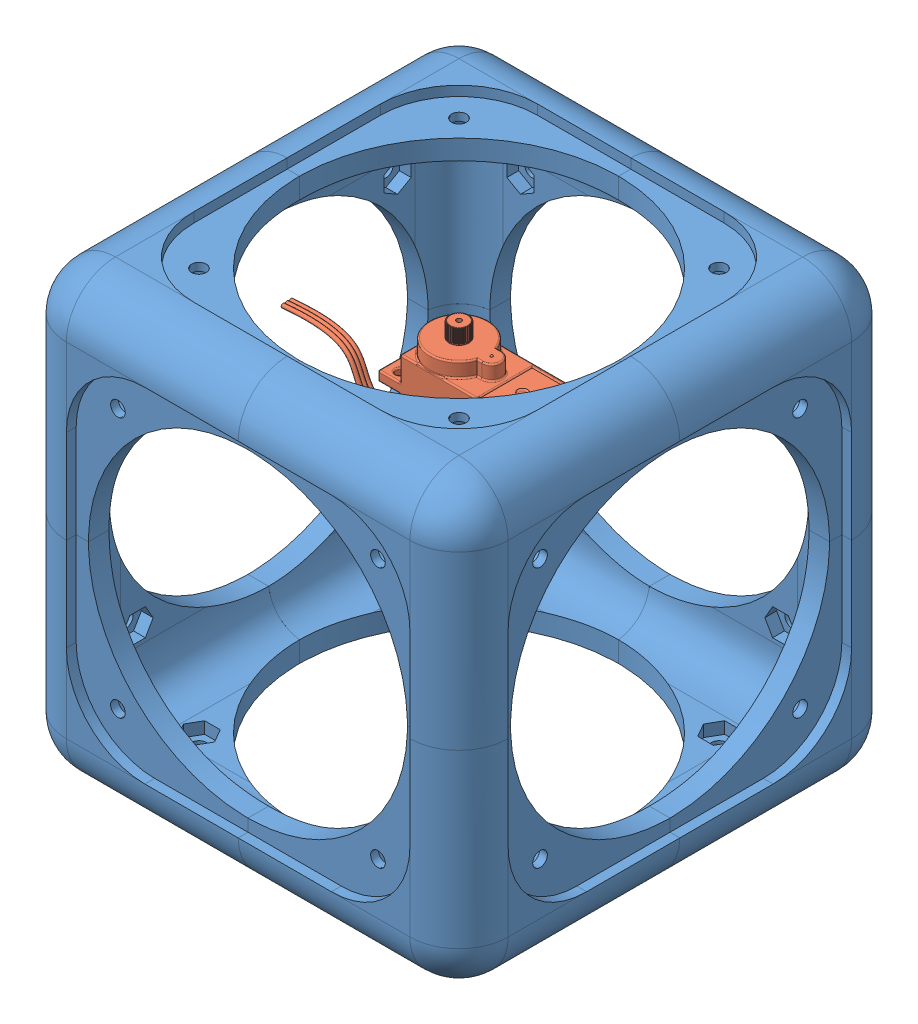
SolidWorks assembly Assem1, configuration Default. Lengths in mm.
Overall size (90 90 90).
9 component instances, 2 part files, 8 mates.
Components (placement in the parent):
- 45cube-1: 45cube [Default] at (-10.9556 29.9167 44.875) size (45.05 45.05 45.05)
- 45cube-2: 45cube [Default] at (56.5444 29.9167 67.375) x (0 0 -1) z (1 0 0) size (45.05 45.05 45.05)
- 45cube-3: 45cube [Default] at (79.0444 29.9167 -0.125) x (-1 0 0) z (0 0 -1) size (45.05 45.05 45.05)
- 45cube-4: 45cube [Default] at (11.5444 29.9167 -22.625) x (0 0 1) z (-1 0 0) size (45.05 45.05 45.05)
- 45cube-5: 45cube [Default] at (56.5444 -37.5833 44.875) x (0 1 0) z (1 0 0) size (45.05 45.05 45.05)
- 45cube-6: 45cube [Default] at (56.5444 -37.5833 -0.125) x (0 1 0) z (0 0 -1) size (45.05 45.05 45.05)
- 45cube-7: 45cube [Default] at (11.5444 -37.5833 44.875) x (0 1 0) z (0 0 1) size (45.05 45.05 45.05)
- 45cube-8: 45cube [Default] at (11.5444 -37.5833 -0.125) x (0 1 0) z (-1 0 0) size (45.05 45.05 45.05)
- Servo HXT900 Micro-1: Servo HXT900 Micro [Valor predeterminado] at (39.5444 12.2222 22.375) size (56.55 29.01 12.2)
Mates (geometry in assembly coordinates):
- Coincident1: coincident anti-aligned: circle of 45cube-1; circle of 45cube-4
- Coincident2: coincident anti-aligned: circle of 45cube-1; circle of 45cube-2
- Coincident3: coincident anti-aligned: circle of 45cube-2; circle of 45cube-3
- Coincident4: coincident anti-aligned: circle of 45cube-7; circle of 45cube-1
- Coincident5: coincident anti-aligned: circle of 45cube-4; circle of 45cube-8
- Coincident6: coincident anti-aligned: circle of 45cube-3; circle of 45cube-6
- Coincident7: coincident anti-aligned: circle of 45cube-2; circle of 45cube-5
- Concentric1: concentric aligned: circle of 45cube-4; circle of Servo HXT900 Micro-1
